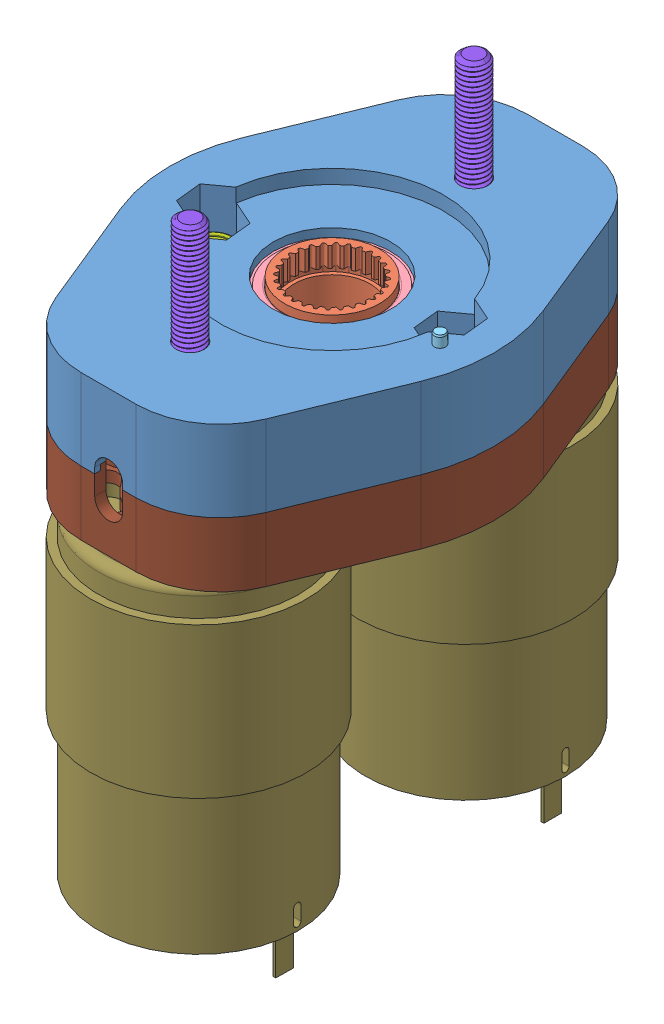
SolidWorks assembly 217-3141-550 STEP, configuration Default. Lengths in mm.
Overall size (58 109.99 86.61).
24 component instances, 13 part files, 0 mates.
Components (placement in the parent):
- 217-3141-001 Rev1-1: 217-3141-001 Rev1 [Default] x (0 0 1) z (-1 0 0) size (80 14.5 58)
- 217-3141-007 Rev1_30T 32DP-1: 217-3141-007 Rev1_30T 32DP [Default] at (0 -7.06 0) x (0 -1 0) z (-0.999183 0 0.040426) size (22.38 25.55 25.47)
- 217-3141-006 Rev1_30T 32DP-1: 217-3141-006 Rev1_30T 32DP [Default] at (0 -8.6182 -23.8887) x (-0.095925 0 -0.995389) z (0 -1 0) size (25.47 25.55 10)
- 217-3141-006 Rev1_30T 32DP-2: 217-3141-006 Rev1_30T 32DP [Default] at (0 -8.7182 23.8887) x (-0.001725 0 0.999999) z (0 -1 0) size (25.47 25.55 10)
- 217-2741-1: 217-2741 [Default] at (0 2.75 0) x (0 -1 0) z (-0.999445 0 -0.033298) size (5 26 26)
- 217-2741-2: 217-2741 [Default] at (0 -13.25 0) x (0 -1 0) z (-0.537831 0 0.843053) size (5 26 26)
- PINL-M020-006-S-1: PINL-M020-006-S [Default] at (22.7445 5.75 3.4184) x (0 1 0) z (-0.890225 0 0.455522) size (6 2 2)
- SSS1032-0188-ZB-1: SSS1032-0188-ZB [Default] at (-0.3489 -10.4932 -27.5094) x (-0.758755 -0.647259 0.073121) z (0.095925 0 0.995389) size (4.91 4.91 5.06)
- SSS1032-0188-ZB-2: SSS1032-0188-ZB [Default] at (-0.0063 -10.5932 27.5262) x (0.762269 -0.647259 0.001315) z (0.001725 0 -0.999999) size (4.91 4.91 5.06)
- NUT-832-NYLOCK-1: NUT-832-NYLOCK [Default] at (19.244 -4.75 -2.0226) x (0.913545 0 0.406737) z (-0.406737 0 0.913545) size (10.2 4.9 8.12)
- NUT-832-NYLOCK-2: NUT-832-NYLOCK [Default] at (-19.244 -4.75 2.0226) x (0.912648 0 0.408747) z (-0.408747 0 0.912648) size (10.2 4.9 8.12)
- 91251A346_91251A346-1: 91251A346_91251A346 [Default] at (0 25.975 25.4) x (1 0 0) z (0 1 0) size (7.92 7.92 27.28)
- 91251A346_91251A346-2: 91251A346_91251A346 [Default] at (0 25.975 -25.4) x (1 0 0) z (0 1 0) size (7.92 7.92 27.28)
- SSA_SSAM3-0008ZC-1: SSA_SSAM3-0008ZC [Default] at (12.5 -17.25 -23.8887) x (0.954123 0 -0.299415) z (0.299415 0 0.954123) size (5.5 11 5.5)
- SSA_SSAM3-0008ZC-2: SSA_SSAM3-0008ZC [Default] at (-12.5 -17.25 -23.8887) x (0.942705 0 -0.333628) z (0.333628 0 0.942705) size (5.5 11 5.5)
- SSA_SSAM3-0008ZC-3: SSA_SSAM3-0008ZC [Default] at (12.5 -17.25 23.8887) x (0.889114 0 0.457686) z (-0.457686 0 0.889114) size (5.5 11 5.5)
- SSA_SSAM3-0008ZC-4: SSA_SSAM3-0008ZC [Default] at (-12.4989 -17.25 23.7224) x (0.972492 0 0.232935) z (-0.232935 0 0.972492) size (5.5 11 5.5)
- SSA_SSA0832-0750ZC-1: SSA_SSA0832-0750ZC [Default] at (19.244 -19.25 -2.0226) x (-0.091926 0 -0.995766) z (-0.995766 0 0.091926) size (6.73 23.11 6.73)
- SSA_SSA0832-0750ZC-2: SSA_SSA0832-0750ZC [Default] at (-19.244 -19.25 2.0226) x (-0.18632 0 -0.982489) z (-0.982489 0 0.18632) size (6.73 23.11 6.73)
- 217-3141-003 Rev1-1: 217-3141-003 Rev1 [Default] at (0 -13 0) x (0 0 1) z (0 1 0) size (80 58 12.5)
- BaneBots RS550-1: BaneBots RS550 [Default] at (0 -69.288 23.8887) x (0.999911 0 0.013308) z (0 1 0) size (38.61 38.57 77.9)
- BaneBots RS550-2: BaneBots RS550 [Default] at (0 -69.288 -23.8887) x (1 0 0) z (0 1 0) size (38.61 38.57 77.9)
- 217-2625-012 Rev1-1: 217-2625-012 Rev1 [Default] at (0 -13.7182 23.8887) x (0.991716 0 0.128446) z (0 1 0) size (8.01 7.94 7.5)
- 217-2625-012 Rev1-2: 217-2625-012 Rev1 [Default] at (0 -13.6182 -23.8887) x (1 0 0) z (0 1 0) size (8.01 7.94 7.5)
